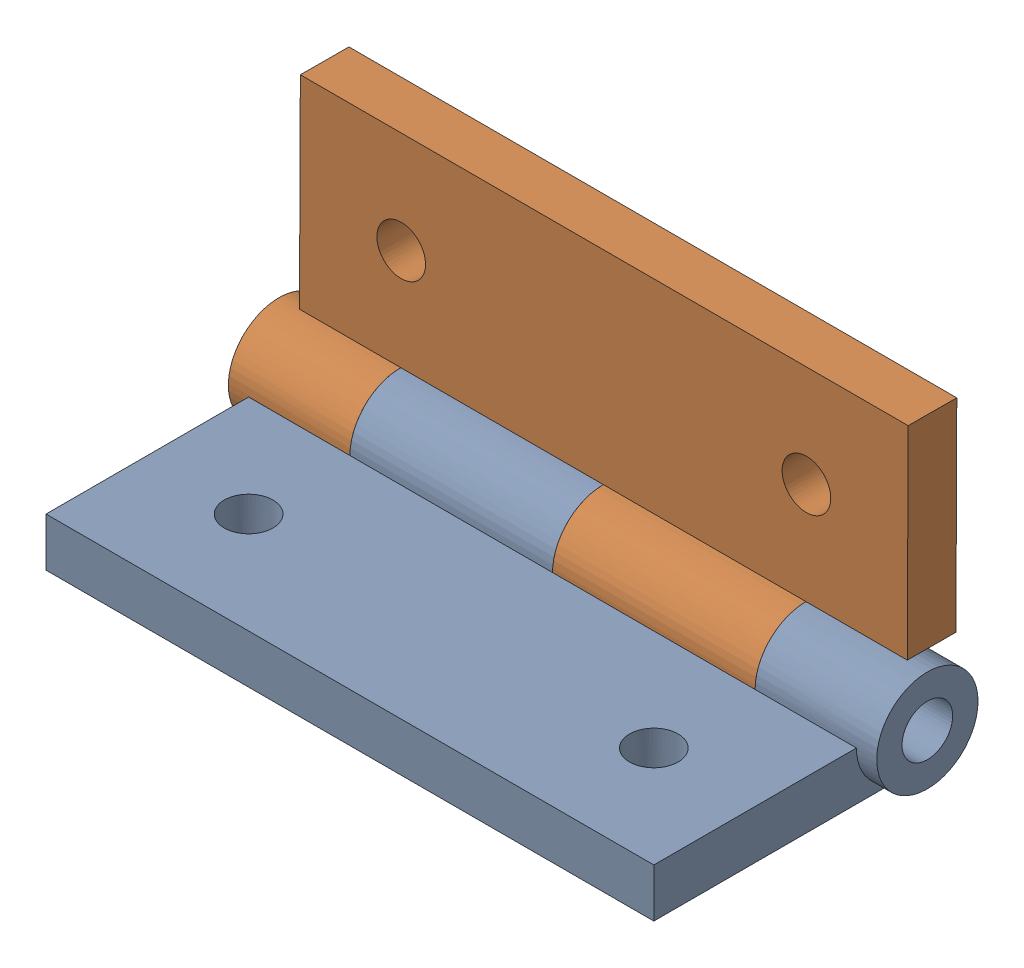
SolidWorks assembly Pack_and_go_Electroporation BoxHinge Full, configuration Default. Lengths in mm.
Overall size (40.64 19.08 19.12).
2 component instances, 1 part files, 2 mates.
Components (placement in the parent):
- Pack_and_go_Electroporation BoxHinge-1: Pack_and_go_Electroporation BoxHinge [Default] at (-53.6638 3.3805 25.2027) size (39.37 6.35 19.05)
- Pack_and_go_Electroporation BoxHinge-2: Pack_and_go_Electroporation BoxHinge [Default] at (-53.6638 14.353 14.1835) x (-1 0 0) z (0 0.999991 -0.004245) size (39.37 6.35 19.05)
Mates (geometry in assembly coordinates):
- Concentric1: concentric anti-aligned: circle of Pack_and_go_Electroporation BoxHinge-1; circle of Pack_and_go_Electroporation BoxHinge-2
- Coincident2: coincident anti-aligned: plane of Pack_and_go_Electroporation BoxHinge-1 through (-66.3638 9.6035 14.0902) normal (-1 0 0); plane of Pack_and_go_Electroporation BoxHinge-2 through (-66.3638 3.267 20.4536) normal (1 0 0)
